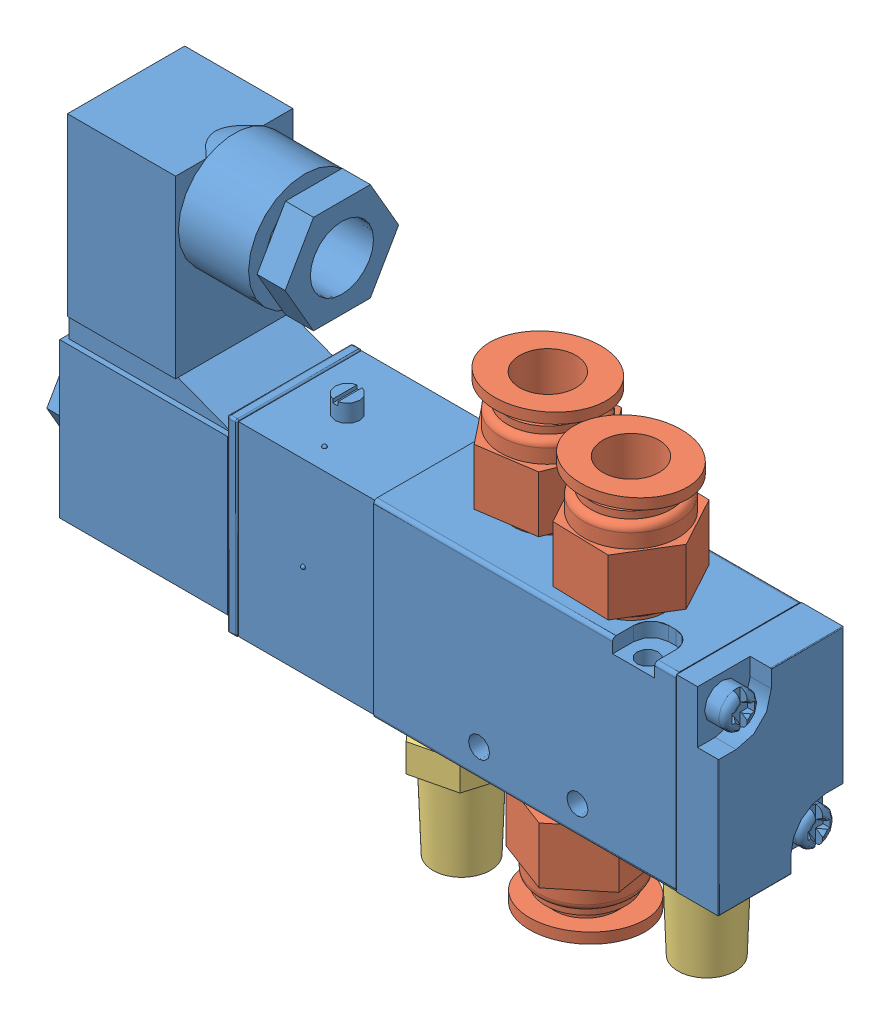
SolidWorks assembly valve, configuration По умолчанию. Lengths in mm.
Overall size (97.78 69.76 26.57).
6 component instances, 3 part files, 5 mates.
Components (placement in the parent):
- соленоид-1: соленоид [По умолчанию] at origin size (97.78 53.2 18.15)
- фитинг-1: фитинг [По умолчанию] at (-8.1727 19.5419 6.5436) x (0.632301 0 -0.774723) z (0.774723 0 0.632301) size (15.4 22.9 15.8)
- фитинг-2: фитинг [По умолчанию] at (8.2686 19.6124 11.148) x (0.757461 0 -0.652881) z (0.652881 0 0.757461) size (15.4 22.9 15.8)
- фитинг-3: фитинг [По умолчанию] at (0 -19.3007 9.3115) x (0.998791 0 0.049164) z (0.049164 0 -0.998791) size (15.4 22.9 15.8)
- выход-1: выход [По умолчанию] at (14.7302 -16.06 6.8203) x (-0.988984 0 -0.148025) z (-0.148025 0 0.988984) size (12.24 25 12.3)
- выход-2: выход [По умолчанию] at (-15.1058 -16.0376 11.8809) x (-0.857609 0 -0.514302) z (-0.514302 0 0.857609) size (12.24 25 12.3)
Mates (geometry in assembly coordinates):
- Концентричный1: concentric: circle of соленоид-1; circle of фитинг-1
- Концентричный2: concentric: circle of соленоид-1; circle of фитинг-2
- Концентричный3: concentric: cylinder of соленоид-1 through (0 -5.5 9.3115) axis (0 -1 0) radius 4.85; cylinder of фитинг-3 through (0 -7.1007 9.3115) axis (0 -1 0) radius 4.85
- Концентричный4: concentric: cylinder of соленоид-1 through (14.7302 -5.5 6.8203) axis (0 -1 0) radius 4.85; cylinder of выход-1 through (14.7302 -5.06 6.8203) axis (0 -1 0) radius 4.85
- Концентричный5: concentric: cylinder of соленоид-1 through (-15.1058 -5.5 11.8809) axis (0 -1 0) radius 4.85; cylinder of выход-2 through (-15.1058 -5.0376 11.8809) axis (0 -1 0) radius 4.85
